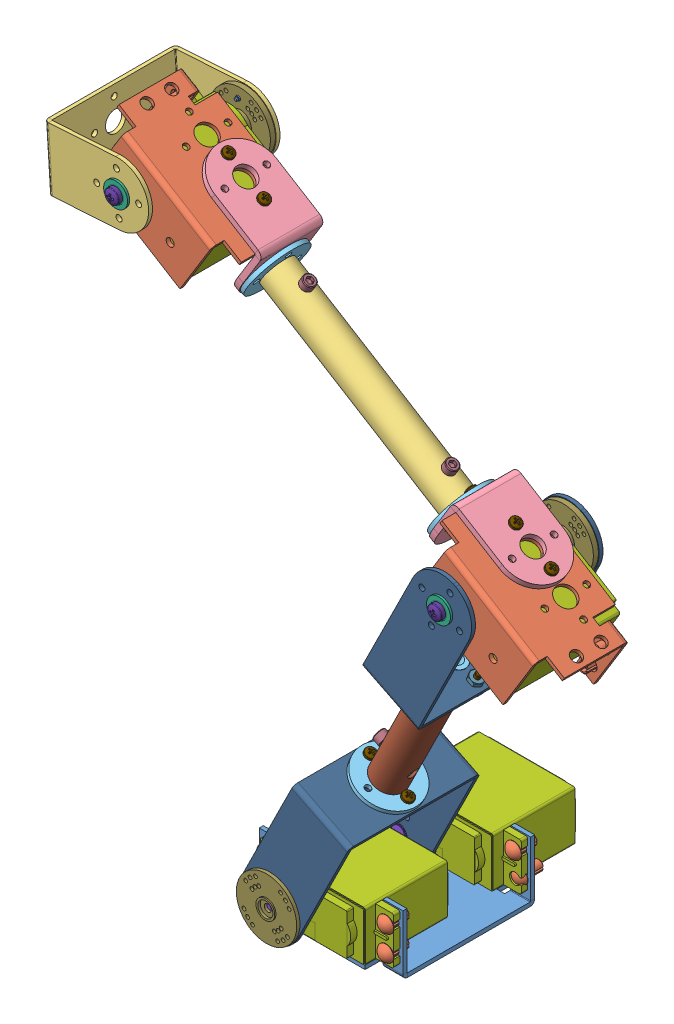
SolidWorks assembly AlumTubeArm-Assy, configuration Default. Lengths in mm.
Overall size (198.02 254.38 96.04).
100 component instances, 21 part files, 161 mates.
Components (placement in the parent):
- asb-13-1: asb-13 [Default] at origin size (57.15 23.83 60.32)
- asb-04-1: asb-04 [Default] at (103.3005 157.352 -10.0457) x (-0.851621 0.524158 0) z (0 0 1) size (57.15 24.21 34.72)
- asb-04-2: asb-04 [Default] at (-25.1454 236.4083 -10.0457) x (-0.851621 0.524158 0) z (0 0 1) size (57.15 24.21 34.72)
- at-06-1: at-06 [Default] at (-4.255 208.2501 -15.4686) x (0 0 1) z (0.851621 -0.524158 0) size (12.7 12.7 85.72)
- asb-06-1: asb-06 [Default] at (78.1303 175.5281 -15.4686) x (-0.851621 0.524158 0) z (0 0 1) size (34.92 27.61 24.59)
- hub-08-1: hub-08 [Default] at (71.4542 161.6524 -15.4686) x (0.524158 0.851621 0) z (0 0 1) size (23.8 16.66 23.8)
- BB-03-1: BB-03 [Default] at (87.3605 150.4009 12.1026) x (0 0 1) z (0.682176 0.731188 0) size (4 9.5 9.5)
- asb-06-2: asb-06 [Default] at (2.4212 222.1258 -15.4686) x (0.851621 -0.524158 0) z (0 0 -1) size (34.92 27.61 24.59)
- hub-08-2: hub-08 [Default] at (-6.9588 209.9143 -15.4686) x (-0.524158 -0.851621 0) z (0 0 1) size (23.8 16.66 23.8)
- Servo_complete-3: Servo_complete [Default] at (29.3908 13.9408 -5.6384) x (-1 0 0) z (0 1 0) size (53 41.78 19.8)
  - Servo_case-1: Servo_case [Default] at origin size (53 38.29 19.8)
  - Output_shaft-1: Output_shaft [Default] at (10 3.0362 0) size (5.71 7.87 5.71)
  - Binding Head Screw_AI-1: Binding Head Screw_AI [CR-BHMS 0.06-80x0.625x0.625-S] at (-17.241 -25.1288 7.741) x (0 1 0) z (0 0 1) size (31.27 3.2 3.2)
  - Binding Head Screw_AI-2: Binding Head Screw_AI [CR-BHMS 0.06-80x0.625x0.625-S] at (-17.241 -25.1288 -7.741) x (0 1 0) z (0 0 1) size (31.27 3.2 3.2)
  - Binding Head Screw_AI-3: Binding Head Screw_AI [CR-BHMS 0.06-80x0.625x0.625-S] at (17.241 -25.1288 7.741) x (0 1 0) z (0 0 1) size (31.27 3.2 3.2)
  - Binding Head Screw_AI-4: Binding Head Screw_AI [CR-BHMS 0.06-80x0.625x0.625-S] at (17.241 -25.1288 -7.741) x (0 1 0) z (0 0 1) size (31.27 3.2 3.2)
- Servo_complete-2: Servo_complete [Default] at (29.3908 13.9408 -56.4511) x (-1 0 0) z (0 1 0) size (53 41.78 19.8)
  - Servo_case-1: Servo_case [Default] at origin size (53 38.29 19.8)
  - Output_shaft-1: Output_shaft [Default] at (10 3.0362 0) size (5.71 7.87 5.71)
  - Binding Head Screw_AI-1: Binding Head Screw_AI [CR-BHMS 0.06-80x0.625x0.625-S] at (-17.241 -25.1288 7.741) x (0 1 0) z (0 0 1) size (31.27 3.2 3.2)
  - Binding Head Screw_AI-2: Binding Head Screw_AI [CR-BHMS 0.06-80x0.625x0.625-S] at (-17.241 -25.1288 -7.741) x (0 1 0) z (0 0 1) size (31.27 3.2 3.2)
  - Binding Head Screw_AI-3: Binding Head Screw_AI [CR-BHMS 0.06-80x0.625x0.625-S] at (17.241 -25.1288 7.741) x (0 1 0) z (0 0 1) size (31.27 3.2 3.2)
  - Binding Head Screw_AI-4: Binding Head Screw_AI [CR-BHMS 0.06-80x0.625x0.625-S] at (17.241 -25.1288 -7.741) x (0 1 0) z (0 0 1) size (31.27 3.2 3.2)
- Servo_complete-1: Servo_complete [Default] at (-32.5692 224.2156 -21.7428) x (-0.851621 0.524158 0) z (-0.524158 -0.851621 0) size (53 41.78 19.8)
  - Servo_case-1: Servo_case [Default] at origin size (53 38.29 19.8)
  - Output_shaft-1: Output_shaft [Default] at (10 3.0362 0) size (5.71 7.87 5.71)
  - Binding Head Screw_AI-1: Binding Head Screw_AI [CR-BHMS 0.06-80x0.625x0.625-S] at (-17.241 -25.1288 7.741) x (0 1 0) z (0 0 1) size (31.27 3.2 3.2)
  - Binding Head Screw_AI-2: Binding Head Screw_AI [CR-BHMS 0.06-80x0.625x0.625-S] at (-17.241 -25.1288 -7.741) x (0 1 0) z (0 0 1) size (31.27 3.2 3.2)
  - Binding Head Screw_AI-3: Binding Head Screw_AI [CR-BHMS 0.06-80x0.625x0.625-S] at (17.241 -25.1288 7.741) x (0 1 0) z (0 0 1) size (31.27 3.2 3.2)
  - Binding Head Screw_AI-4: Binding Head Screw_AI [CR-BHMS 0.06-80x0.625x0.625-S] at (17.241 -25.1288 -7.741) x (0 1 0) z (0 0 1) size (31.27 3.2 3.2)
- BB-03-2: BB-03 [Default] at (-41.0855 229.4572 12.1026) x (0 0 1) z (-0.999072 -0.043064 0) size (4 9.5 9.5)
- Servo_complete-4: Servo_complete [Default] at (95.8767 145.1594 -21.7428) x (-0.851621 0.524158 0) z (-0.524158 -0.851621 0) size (53 41.78 19.8)
  - Servo_case-1: Servo_case [Default] at origin size (53 38.29 19.8)
  - Output_shaft-1: Output_shaft [Default] at (10 3.0362 0) size (5.71 7.87 5.71)
  - Binding Head Screw_AI-1: Binding Head Screw_AI [CR-BHMS 0.06-80x0.625x0.625-S] at (-17.241 -25.1288 7.741) x (0 1 0) z (0 0 1) size (31.27 3.2 3.2)
  - Binding Head Screw_AI-2: Binding Head Screw_AI [CR-BHMS 0.06-80x0.625x0.625-S] at (-17.241 -25.1288 -7.741) x (0 1 0) z (0 0 1) size (31.27 3.2 3.2)
  - Binding Head Screw_AI-3: Binding Head Screw_AI [CR-BHMS 0.06-80x0.625x0.625-S] at (17.241 -25.1288 7.741) x (0 1 0) z (0 0 1) size (31.27 3.2 3.2)
  - Binding Head Screw_AI-4: Binding Head Screw_AI [CR-BHMS 0.06-80x0.625x0.625-S] at (17.241 -25.1288 -7.741) x (0 1 0) z (0 0 1) size (31.27 3.2 3.2)
- asb-10-1: asb-10 [Default] at (39.9278 55.1721 -14.8713) x (0 0 -1) z (-0.895109 0.445847 0) size (52.25 58.34 24.61)
- hub-08-3: hub-08 [Default] at (39.22 53.7511 -14.8713) x (-0.895109 0.445847 0) z (0 0 -1) size (23.8 16.66 23.8)
- asb-10-2: asb-10 [Default] at (66.8235 109.1696 -14.8713) x (0 0 -1) z (0.895109 -0.445847 0) size (52.25 58.34 24.61)
- hub-08-4: hub-08 [Default] at (67.5313 110.5906 -14.8713) x (-0.895109 0.445847 0) z (0 0 1) size (23.8 16.66 23.8)
- at-05-1: at-05 [Default] at (66.1157 107.7486 -14.8713) x (0 0 -1) z (-0.445847 -0.895109 0) size (12.7 12.7 57.15)
- ServoHornPlastic-1: ServoHornPlastic [Default] at (87.3605 150.4009 -39.4712) x (0.649855 0.760058 0) z (-0.760058 0.649855 0) size (24 5 24)
- ServoHornPlastic-2: ServoHornPlastic [Default] at (-41.0855 229.4572 -39.4712) x (0.649855 0.760058 0) z (-0.760058 0.649855 0) size (24 5 24)
- 4-40 x 0.250 SHCS (SHS-01)-1: 4-40 x 0.250 SHCS (SHS-01) [Default] at (8.6763 211.088 -15.4686) x (-0.524158 -0.851621 0) z (0.750627 -0.461998 0.472352) size (9.19 4.65 4.65)
- 4-40 x 0.250 SHCS (SHS-01)-2: 4-40 x 0.250 SHCS (SHS-01) [Default] at (65.4581 176.1397 -15.4686) x (-0.524158 -0.851621 0) z (0.750627 -0.461998 0.472352) size (9.19 4.65 4.65)
- Nut Hex 2-56 (SN-02)-1: Nut Hex 2-56 (SN-02) [Default] at (-4.6145 218.2541 -15.4686) x (0 0 -1) z (-0.851621 0.524158 0) size (4.78 5.51 1.68)
- Nut Hex 2-56 (SN-02)-2: Nut Hex 2-56 (SN-02) [Default] at (-13.3482 204.0641 -15.4686) x (0 0 -1) z (-0.851621 0.524158 0) size (4.78 5.51 1.68)
- Washer Lock M3-1: Washer Lock M3 [Default] at (87.3605 150.4009 7.3152) x (0 0 -1) z (-0.98149 0.191515 0) size (0.79 5.99 5.99)
- Nut Hex M3-1: Nut Hex M3 [Default] at (87.3605 150.4009 2.8912) x (-0.979989 -0.199051 0) z (0 0 -1) size (5.5 6.35 2.9)
- Nut Hex 2-56 (SN-02)-3: Nut Hex 2-56 (SN-02) [Default] at (69.1098 153.3126 -15.4686) x (0 0 1) z (0.851621 -0.524158 0) size (4.78 5.51 1.68)
- Nut Hex 2-56 (SN-02)-4: Nut Hex 2-56 (SN-02) [Default] at (77.8435 167.5026 -15.4686) x (0 0 1) z (0.851621 -0.524158 0) size (4.78 5.51 1.68)
- M3 X 8 LG PHMS (PHS-00)-1: M3 X 8 LG PHMS (PHS-00) [Default] at (87.3605 150.4009 14.5026) x (0 0 -1) z (-0.98149 0.191515 0) size (10.37 5.6 5.6)
- Washer Lock M3-2: Washer Lock M3 [Default] at (-41.0855 229.4572 8.1026) x (0 0 1) z (-0.996303 -0.085907 0) size (0.79 5.99 5.99)
- M3 X 8 LG PHMS (PHS-00)-2: M3 X 8 LG PHMS (PHS-00) [Default] at (-41.0855 229.4572 14.5026) x (0 0 -1) z (0.999989 0.004703 0) size (10.37 5.6 5.6)
- Nut Hex 2-56 (SN-02)-5: Nut Hex 2-56 (SN-02) [Default] at (-41.0855 229.4572 4.1148) x (0.923728 0.383049 0) z (0 0 -1) size (4.78 5.51 1.68)
- 2-56 X 0.250 PHS (PHS-02)-5: 2-56 X 0.250 PHS (PHS-02) [Default] at (71.776 171.2371 -15.4686) x (0.851621 -0.524158 0) z (0 0 1) size (7.89 4.24 4.24)
- 2-56 X 0.250 PHS (PHS-02)-6: 2-56 X 0.250 PHS (PHS-02) [Default] at (63.0423 157.0471 -15.4686) x (0.851621 -0.524158 0) z (0 0 1) size (7.89 4.24 4.24)
- #2 X 0.250 PHTS (PHTS-01)-1: #2 X 0.250 PHTS (PHTS-01) [Default] at (94.8178 146.6865 -40.9952) x (0 0 1) z (-1 0 0) size (6.96 5.97 5.51)
- #2 X 0.250 PHTS (PHTS-01)-2: #2 X 0.250 PHTS (PHTS-01) [Default] at (79.9031 154.1154 -40.9952) x (0 0 1) z (-1 0 0) size (6.96 5.97 5.51)
- Nut Hex 2-56 (SN-02)-10: Nut Hex 2-56 (SN-02) [Default] at (45.9582 48.593 -14.8713) x (0 0 -1) z (-0.445847 -0.895109 0) size (4.78 5.51 1.68)
- Nut Hex 2-56 (SN-02)-11: Nut Hex 2-56 (SN-02) [Default] at (31.0436 56.0219 -14.8713) x (0 0 -1) z (-0.445847 -0.895109 0) size (4.78 5.51 1.68)
- Nut Hex 2-56 (SN-02)-12: Nut Hex 2-56 (SN-02) [Default] at (75.7077 108.3199 -14.8713) x (0 0 -1) z (0.445847 0.895109 0) size (4.78 5.51 1.68)
- Nut Hex 2-56 (SN-02)-13: Nut Hex 2-56 (SN-02) [Default] at (60.793 115.7488 -14.8713) x (0 0 -1) z (0.445847 0.895109 0) size (4.78 5.51 1.68)
- 4-40 x 0.250 SHCS (SHS-01)-3: 4-40 x 0.250 SHCS (SHS-01) [Default] at (36.6519 69.2185 -14.8713) x (0.895109 -0.445847 0) z (-0.344213 -0.691063 -0.635571) size (9.19 4.65 4.65)
- 4-40 x 0.250 SHCS (SHS-01)-4: 4-40 x 0.250 SHCS (SHS-01) [Default] at (53.6387 103.3222 -14.8713) x (0.895109 -0.445847 0) z (-0.351192 -0.705075 -0.616063) size (9.19 4.65 4.65)
- 2-56 X 0.250 PHS (PHS-02)-11: 2-56 X 0.250 PHS (PHS-02) [Default] at (57.9562 110.0534 -14.8713) x (0.445847 0.895109 0) z (-0.895109 0.445847 0) size (7.89 4.24 4.24)
- 2-56 X 0.250 PHS (PHS-02)-12: 2-56 X 0.250 PHS (PHS-02) [Default] at (72.8709 102.6246 -14.8713) x (0.445847 0.895109 0) z (-0.895109 0.445847 0) size (7.89 4.24 4.24)
- 2-56 X 0.250 PHS (PHS-02)-13: 2-56 X 0.250 PHS (PHS-02) [Default] at (33.8804 61.7172 -14.8713) x (-0.445847 -0.895109 0) z (-0.895109 0.445847 0) size (7.89 4.24 4.24)
- 2-56 X 0.250 PHS (PHS-02)-14: 2-56 X 0.250 PHS (PHS-02) [Default] at (48.795 54.2883 -14.8713) x (-0.445847 -0.895109 0) z (-0.895109 0.445847 0) size (7.89 4.24 4.24)
- #2 X 0.250 PHTS (PHTS-01)-3: #2 X 0.250 PHTS (PHTS-01) [Default] at (-40.5533 221.1303 -40.9952) x (0 0 1) z (-1 0 0) size (6.96 5.97 5.51)
- #2 X 0.250 PHTS (PHTS-01)-4: #2 X 0.250 PHTS (PHTS-01) [Default] at (-41.6176 237.7841 -40.9952) x (0 0 1) z (-1 0 0) size (6.96 5.97 5.51)
- 2-56 X 0.250 PHS (PHS-02)-7: 2-56 X 0.250 PHS (PHS-02) [Default] at (-8.9317 230.9625 -15.4686) x (-0.524158 -0.851621 0) z (0 0 1) size (7.89 4.24 4.24)
- 2-56 X 0.250 PHS (PHS-02)-8: 2-56 X 0.250 PHS (PHS-02) [Default] at (-23.1218 239.6962 -15.4686) x (-0.524158 -0.851621 0) z (0 0 1) size (7.89 4.24 4.24)
- 2-56 X 0.250 PHS (PHS-02)-9: 2-56 X 0.250 PHS (PHS-02) [Default] at (91.1341 169.3737 -15.4686) x (-0.524158 -0.851621 0) z (0 0 1) size (7.89 4.24 4.24)
- 2-56 X 0.250 PHS (PHS-02)-10: 2-56 X 0.250 PHS (PHS-02) [Default] at (105.3242 160.64 -15.4686) x (-0.524158 -0.851621 0) z (0 0 1) size (7.89 4.24 4.24)
- Nut Hex 2-56 (SN-02)-6: Nut Hex 2-56 (SN-02) [Default] at (-12.6329 224.949 -15.4686) x (0.572108 -0.352123 0.740744) z (-0.524158 -0.851621 0) size (4.78 5.51 1.68)
- Nut Hex 2-56 (SN-02)-7: Nut Hex 2-56 (SN-02) [Default] at (-26.8229 233.6827 -15.4686) x (0.572108 -0.352123 0.740744) z (-0.524158 -0.851621 0) size (4.78 5.51 1.68)
- Nut Hex 2-56 (SN-02)-8: Nut Hex 2-56 (SN-02) [Default] at (101.623 154.6265 -15.4686) x (0.572108 -0.352123 0.740744) z (-0.524158 -0.851621 0) size (4.78 5.51 1.68)
- Nut Hex 2-56 (SN-02)-9: Nut Hex 2-56 (SN-02) [Default] at (87.4329 163.3602 -15.4686) x (0.572108 -0.352123 0.740744) z (-0.524158 -0.851621 0) size (4.78 5.51 1.68)
- NSRF-01-1: NSRF-01 [Default] at (118.9364 136.8377 -28.5121) x (0 0 1) z (-1 0 0) size (9.65 6.35 6.35)
- NSRF-01-2: NSRF-01 [Default] at (113.6948 128.3215 -28.5121) x (0 0 1) z (-1 0 0) size (9.65 6.35 6.35)
- NSRF-01-3: NSRF-01 [Default] at (78.0586 161.9973 -28.5121) x (0 0 1) z (-1 0 0) size (9.65 6.35 6.35)
- NSRF-01-4: NSRF-01 [Default] at (72.817 153.481 -28.5121) x (0 0 1) z (-1 0 0) size (9.65 6.35 6.35)
- NSRF-01-5: NSRF-01 [Default] at (-9.5096 215.8939 -28.5121) x (0 0 1) z (-1 0 0) size (9.65 6.35 6.35)
- NSRF-01-6: NSRF-01 [Default] at (-14.7511 207.3777 -28.5121) x (0 0 1) z (-1 0 0) size (9.65 6.35 6.35)
- NSRF-01-7: NSRF-01 [Default] at (-50.3874 241.0535 -28.5121) x (0 0 1) z (-1 0 0) size (9.65 6.35 6.35)
- NSRF-01-8: NSRF-01 [Default] at (-55.6289 232.5373 -28.5121) x (0 0 1) z (-1 0 0) size (9.65 6.35 6.35)
- NSRF-01-9: NSRF-01 [Default] at (5.3908 18.9408 -49.6818) x (0 0 -1) z (1 0 0) size (9.65 6.35 6.35)
- NSRF-01-10: NSRF-01 [Default] at (5.3908 8.9408 -49.6818) x (0 0 -1) z (1 0 0) size (9.65 6.35 6.35)
- NSRF-01-11: NSRF-01 [Default] at (5.3908 18.9408 1.1309) x (0 0 -1) z (1 0 0) size (9.65 6.35 6.35)
- NSRF-01-12: NSRF-01 [Default] at (5.3908 8.9408 1.1309) x (0 0 -1) z (1 0 0) size (9.65 6.35 6.35)
- NSRF-01-13: NSRF-01 [Default] at (53.3908 18.9408 1.1309) x (0 0 -1) z (1 0 0) size (9.65 6.35 6.35)
- NSRF-01-14: NSRF-01 [Default] at (53.3908 8.9408 1.1309) x (0 0 -1) z (1 0 0) size (9.65 6.35 6.35)
- NSRF-01-15: NSRF-01 [Default] at (53.3908 18.9408 -49.6818) x (0 0 -1) z (1 0 0) size (9.65 6.35 6.35)
- NSRF-01-16: NSRF-01 [Default] at (53.3908 8.9408 -52.1818) x (0 0 -1) z (1 0 0) size (9.65 6.35 6.35)
- asb-09-1: asb-09 [Default] at (-69.6023 227.6349 -14.8713) x (0 0 1) z (-0.063773 0.997964 0) size (52.25 40.87 24.61)
- ServoHornPlastic-3: ServoHornPlastic [Default] at (19.3908 13.9408 12.5376) x (-0.658562 0.752526 0) z (0.752526 0.658562 0) size (24 5 24)
- ServoHornPlastic-4: ServoHornPlastic [Default] at (19.3908 13.9408 -40.9952) x (-0.658562 0.752526 0) z (0.752526 0.658562 0) size (24 5 24)
Mates (geometry in assembly coordinates):
- Concentric1: concentric anti-aligned: cylinder of at-06-1; cylinder of 4-40 x 0.250 SHCS (SHS-01)-1
- Tangent1: tangent anti-aligned: cylinder of at-06-1; plane of 4-40 x 0.250 SHCS (SHS-01)-1
- Concentric2: concentric anti-aligned: cylinder of at-06-1; cylinder of 4-40 x 0.250 SHCS (SHS-01)-2
- Tangent2: tangent anti-aligned: cylinder of at-06-1; plane of 4-40 x 0.250 SHCS (SHS-01)-2
- Coincident1: coincident anti-aligned: plane of asb-06-1 through (96.2055 161.7189 -15.4686) normal (-0.524158 -0.851621 0); plane of asb-04-1 through (147.7167 130.0147 -10.0457) normal (0.524158 0.851621 0)
- Concentric3: concentric aligned: cylinder of asb-06-1; cylinder of asb-04-1
- Concentric4: concentric aligned: cylinder of asb-06-1; cylinder of asb-04-1
- Concentric6: concentric aligned: cylinder of asb-04-1; cylinder of Washer Lock M3-1
- Coincident2: coincident anti-aligned: plane of asb-04-1 through (146.9178 128.7168 7.3152) normal (0 0 1); plane of Washer Lock M3-1
- Concentric7: concentric anti-aligned: cylinder of asb-04-1; cylinder of Nut Hex M3-1
- Coincident3: coincident anti-aligned: plane of asb-04-1 through (122.3345 188.2774 5.7912) normal (0 0 -1); plane of Nut Hex M3-1
- Coincident5: coincident anti-aligned: plane of asb-06-2 through (-18.0504 232.0414 -15.4686) normal (-0.524158 -0.851621 0); plane of asb-04-2 through (19.2707 209.0709 -10.0457) normal (0.524158 0.851621 0)
- Concentric8: concentric aligned: cylinder of asb-06-2; cylinder of asb-04-2
- Concentric9: concentric aligned: cylinder of asb-06-2; cylinder of asb-04-2
- Concentric12: concentric anti-aligned: cylinder of asb-06-2; cylinder of Nut Hex 2-56 (SN-02)-1
- Coincident8: coincident anti-aligned: plane of asb-06-2 through (-7.5537 210.2804 -15.4686) normal (-0.851621 0.524158 0); plane of Nut Hex 2-56 (SN-02)-1
- Concentric13: concentric anti-aligned: cylinder of asb-06-2; cylinder of Nut Hex 2-56 (SN-02)-2
- Coincident9: coincident anti-aligned: plane of asb-06-2 through (-7.5537 210.2804 -15.4686) normal (-0.851621 0.524158 0); plane of Nut Hex 2-56 (SN-02)-2
- Concentric14: concentric anti-aligned: cylinder of hub-08-1; cylinder of at-06-1
- Concentric15: concentric anti-aligned: cylinder of hub-08-1; cylinder of at-06-1
- Concentric16: concentric aligned: cylinder of hub-08-2; cylinder of at-06-1
- Concentric17: concentric anti-aligned: cylinder of asb-06-1; cylinder of hub-08-1
- Coincident10: coincident anti-aligned: plane of asb-06-1 through (76.9321 173.5813 -27.7622) normal (-0.851621 0.524158 0); plane of hub-08-1 through (70.1022 162.4845 -37.2766) normal (0.851621 -0.524158 0)
- Concentric18: concentric anti-aligned: cylinder of asb-06-1; cylinder of hub-08-1
- Concentric19: concentric anti-aligned: cylinder of asb-06-1; cylinder of Nut Hex 2-56 (SN-02)-3
- Coincident11: coincident anti-aligned: plane of asb-06-1 through (72.049 161.2863 -15.4686) normal (0.851621 -0.524158 0); plane of Nut Hex 2-56 (SN-02)-3
- Concentric20: concentric anti-aligned: cylinder of asb-06-1; cylinder of Nut Hex 2-56 (SN-02)-4
- Coincident12: coincident anti-aligned: plane of asb-06-1 through (72.049 161.2863 -15.4686) normal (0.851621 -0.524158 0); plane of Nut Hex 2-56 (SN-02)-4
- Coincident13: coincident aligned: plane of asb-06-1 through (96.2055 161.7189 -15.4686) normal (-0.524158 -0.851621 0); plane of asb-06-2 through (-18.0504 232.0414 -15.4686) normal (-0.524158 -0.851621 0)
- Concentric21: concentric anti-aligned: cylinder of asb-06-1; cylinder of asb-06-2
- Coincident16: coincident anti-aligned: plane of Washer Lock M3-1; plane of BB-03-1 through (89.0641 148.8115 8.1026) normal (0 0 -1)
- Concentric27: concentric anti-aligned: cylinder of asb-06-2; cylinder of hub-08-2
- Coincident19: coincident anti-aligned: plane of asb-06-2 through (1.223 220.179 -3.175) normal (0.851621 -0.524158 0); plane of hub-08-2 through (-5.6069 209.0822 -37.2766) normal (-0.851621 0.524158 0)
- Concentric28: concentric anti-aligned: cylinder of asb-06-2; cylinder of hub-08-2
- Concentric341: concentric anti-aligned: cylinder of BB-03-2; cylinder of Washer Lock M3-2
- Coincident241: coincident anti-aligned: plane of BB-03-2 through (-41.2577 233.4535 8.1026) normal (0 0 -1); plane of Washer Lock M3-2
- Coincident25: coincident anti-aligned: plane of asb-04-2 through (18.4719 207.773 7.3152) normal (0 0 1); plane of Washer Lock M3-2
- Concentric371: concentric anti-aligned: cylinder of asb-04-2; cylinder of Nut Hex 2-56 (SN-02)-5
- Coincident271: coincident anti-aligned: plane of asb-04-2 through (-6.1114 267.3336 5.7912) normal (0 0 -1); plane of Nut Hex 2-56 (SN-02)-5
- Coincident272: coincident anti-aligned: plane of asb-13-1 through (-36.2013 23.8252 -3.9624) normal (0 0 1); plane of Servo_complete-3/Servo_case-1 through (55.8908 23.3408 -3.9624) normal (0 0 -1)
- Parallel1: parallel aligned: plane of asb-13-1 through (57.15 23.8252 -52.3041) normal (1 0 0); plane of Servo_complete-3/Servo_case-1 through (55.8908 4.5408 -3.9624) normal (1 0 0)
- Coincident273: coincident anti-aligned: plane of asb-13-1 through (-36.2013 23.8252 -54.7751) normal (0 0 1); plane of Servo_complete-2/Servo_case-1 through (55.8908 23.3408 -54.7751) normal (0 0 -1)
- Parallel2: parallel aligned: plane of asb-13-1 through (57.15 23.8252 -8.0209) normal (1 0 0); plane of Servo_complete-2/Servo_case-1 through (55.8908 4.5408 -54.7751) normal (1 0 0)
- Concentric376: concentric aligned: cylinder of asb-13-1; cylinder of Servo_complete-3/Servo_case-1
- Concentric377: concentric aligned: cylinder of asb-13-1; cylinder of Servo_complete-2/Servo_case-1
- Coincident275: coincident anti-aligned: plane of asb-04-2 through (18.4719 207.773 -23.4188) normal (0 0 -1); plane of Servo_complete-1/Servo_case-1 through (-60.0643 230.1005 -23.4188) normal (0 0 1)
- Parallel3: parallel aligned: plane of asb-04-2 through (19.2707 209.0709 -10.0457) normal (0.524158 0.851621 0); plane of Servo_complete-1/Servo_case-1 through (-11.5076 222.8774 -29.9978) normal (0.524158 0.851621 0)
- Coincident276: coincident anti-aligned: plane of asb-04-1 through (146.9178 128.7168 -23.4188) normal (0 0 -1); plane of Servo_complete-4/Servo_case-1 through (68.3816 151.0443 -23.4188) normal (0 0 1)
- Parallel4: parallel aligned: plane of asb-04-1 through (147.7167 130.0147 -10.0457) normal (0.524158 0.851621 0); plane of Servo_complete-4/Servo_case-1 through (116.9384 143.8212 -29.9978) normal (0.524158 0.851621 0)
- Concentric380: concentric aligned: cylinder of BB-03-1; cylinder of M3 X 8 LG PHMS (PHS-00)-1
- Coincident277: coincident anti-aligned: plane of BB-03-1 through (88.4572 149.3777 12.1026) normal (0 0 1); plane of M3 X 8 LG PHMS (PHS-00)-1
- Concentric3811: concentric anti-aligned: cylinder of hub-08-1; cylinder of 2-56 X 0.250 PHS (PHS-02)-5
- Coincident2781: coincident anti-aligned: plane of hub-08-1 through (68.7503 163.3166 -37.2766) normal (-0.851621 0.524158 0); plane of 2-56 X 0.250 PHS (PHS-02)-5
- Concentric3821: concentric anti-aligned: cylinder of hub-08-1; cylinder of 2-56 X 0.250 PHS (PHS-02)-6
- Coincident2791: coincident anti-aligned: plane of hub-08-1 through (68.7503 163.3166 -37.2766) normal (-0.851621 0.524158 0); plane of 2-56 X 0.250 PHS (PHS-02)-6
- Concentric383: concentric anti-aligned: cylinder of Servo_complete-4/Servo_case-1; cylinder of ServoHornPlastic-1
- Concentric386: concentric aligned: cylinder of BB-03-2; cylinder of M3 X 8 LG PHMS (PHS-00)-2
- Coincident283: coincident anti-aligned: plane of BB-03-2 through (-41.1501 230.9558 12.1026) normal (0 0 1); plane of M3 X 8 LG PHMS (PHS-00)-2
- Concentric387: concentric anti-aligned: cylinder of Servo_complete-1/Servo_case-1; cylinder of ServoHornPlastic-2
- Concentric3901: concentric aligned: cylinder of asb-06-2; cylinder of 2-56 X 0.250 PHS (PHS-02)-7
- Coincident2871: coincident anti-aligned: plane of asb-06-2 through (-16.8522 233.9882 -15.4686) normal (0.524158 0.851621 0); plane of 2-56 X 0.250 PHS (PHS-02)-7
- Concentric3911: concentric aligned: cylinder of asb-06-2; cylinder of 2-56 X 0.250 PHS (PHS-02)-8
- Coincident2881: coincident anti-aligned: plane of asb-06-2 through (-16.8522 233.9882 -15.4686) normal (0.524158 0.851621 0); plane of 2-56 X 0.250 PHS (PHS-02)-8
- Concentric3921: concentric aligned: cylinder of asb-06-1; cylinder of 2-56 X 0.250 PHS (PHS-02)-9
- Coincident2891: coincident anti-aligned: plane of asb-06-1 through (97.4037 163.6657 -15.4686) normal (0.524158 0.851621 0); plane of 2-56 X 0.250 PHS (PHS-02)-9
- Concentric3931: concentric aligned: cylinder of asb-06-1; cylinder of 2-56 X 0.250 PHS (PHS-02)-10
- Coincident2901: coincident anti-aligned: plane of asb-06-1 through (97.4037 163.6657 -15.4686) normal (0.524158 0.851621 0); plane of 2-56 X 0.250 PHS (PHS-02)-10
- Concentric3941: concentric anti-aligned: cylinder of asb-04-2; cylinder of Nut Hex 2-56 (SN-02)-6
- Coincident2911: coincident anti-aligned: plane of asb-04-2 through (18.4719 207.773 -10.0457) normal (-0.524158 -0.851621 0); plane of Nut Hex 2-56 (SN-02)-6
- Concentric3951: concentric anti-aligned: cylinder of asb-04-2; cylinder of Nut Hex 2-56 (SN-02)-7
- Coincident2921: coincident anti-aligned: plane of asb-04-2 through (18.4719 207.773 -10.0457) normal (-0.524158 -0.851621 0); plane of Nut Hex 2-56 (SN-02)-7
- Concentric3961: concentric anti-aligned: cylinder of asb-04-1; cylinder of Nut Hex 2-56 (SN-02)-8
- Coincident2931: coincident anti-aligned: plane of asb-04-1 through (146.9178 128.7168 -10.0457) normal (-0.524158 -0.851621 0); plane of Nut Hex 2-56 (SN-02)-8
- Concentric3971: concentric anti-aligned: cylinder of asb-04-1; cylinder of Nut Hex 2-56 (SN-02)-9
- Coincident2941: coincident anti-aligned: plane of asb-04-1 through (146.9178 128.7168 -10.0457) normal (-0.524158 -0.851621 0); plane of Nut Hex 2-56 (SN-02)-9
- Concentric3981: concentric aligned: cylinder of Servo_complete-4/Servo_case-1; cylinder of NSRF-01-1
- Coincident2951: coincident anti-aligned: plane of Servo_complete-4/Servo_case-1 through (113.5176 123.2639 -25.9188) normal (0 0 -1); plane of NSRF-01-1 through (118.9364 138.1155 -25.9188) normal (0 0 1)
- Concentric3991: concentric aligned: cylinder of Servo_complete-4/Servo_case-1; cylinder of NSRF-01-2
- Coincident2961: coincident anti-aligned: plane of Servo_complete-4/Servo_case-1 through (113.5176 123.2639 -25.9188) normal (0 0 -1); plane of NSRF-01-2 through (113.6948 129.5993 -25.9188) normal (0 0 1)
- Concentric4001: concentric aligned: cylinder of Servo_complete-4/Servo_case-1; cylinder of NSRF-01-3
- Coincident2971: coincident anti-aligned: plane of Servo_complete-4/Servo_case-1 through (68.3816 151.0443 -25.9188) normal (0 0 -1); plane of NSRF-01-3 through (78.0586 163.2751 -25.9188) normal (0 0 1)
- Concentric4011: concentric aligned: cylinder of Servo_complete-4/Servo_case-1; cylinder of NSRF-01-4
- Coincident2981: coincident anti-aligned: plane of Servo_complete-4/Servo_case-1 through (68.3816 151.0443 -25.9188) normal (0 0 -1); plane of NSRF-01-4 through (72.817 154.7589 -25.9188) normal (0 0 1)
- Concentric4021: concentric aligned: cylinder of Servo_complete-1/Servo_case-1; cylinder of NSRF-01-5
- Coincident2991: coincident anti-aligned: plane of Servo_complete-1/Servo_case-1 through (-14.9284 202.3202 -25.9188) normal (0 0 -1); plane of NSRF-01-5 through (-9.5096 217.1717 -25.9188) normal (0 0 1)
- Concentric4031: concentric aligned: cylinder of Servo_complete-1/Servo_case-1; cylinder of NSRF-01-6
- Coincident3001: coincident anti-aligned: plane of Servo_complete-1/Servo_case-1 through (-14.9284 202.3202 -25.9188) normal (0 0 -1); plane of NSRF-01-6 through (-14.7511 208.6555 -25.9188) normal (0 0 1)
- Concentric4041: concentric aligned: cylinder of Servo_complete-1/Servo_case-1; cylinder of NSRF-01-7
- Coincident3011: coincident anti-aligned: plane of Servo_complete-1/Servo_case-1 through (-60.0643 230.1005 -25.9188) normal (0 0 -1); plane of NSRF-01-7 through (-50.3874 242.3313 -25.9188) normal (0 0 1)
- Concentric4051: concentric aligned: cylinder of Servo_complete-1/Servo_case-1; cylinder of NSRF-01-8
- Coincident3021: coincident anti-aligned: plane of Servo_complete-1/Servo_case-1 through (-60.0643 230.1005 -25.9188) normal (0 0 -1); plane of NSRF-01-8 through (-55.6289 233.8151 -25.9188) normal (0 0 1)
- Concentric4061: concentric aligned: cylinder of Servo_complete-2/Servo_case-1; cylinder of NSRF-01-9
- Coincident3031: coincident anti-aligned: plane of Servo_complete-2/Servo_case-1 through (2.8908 23.3408 -52.2751) normal (0 0 1); plane of NSRF-01-9 through (5.3908 20.2186 -52.2751) normal (0 0 -1)
- Concentric4071: concentric aligned: cylinder of Servo_complete-2/Servo_case-1; cylinder of NSRF-01-10
- Coincident3041: coincident anti-aligned: plane of Servo_complete-2/Servo_case-1 through (2.8908 23.3408 -52.2751) normal (0 0 1); plane of NSRF-01-10 through (5.3908 10.2186 -52.2751) normal (0 0 -1)
- Concentric4081: concentric aligned: cylinder of Servo_complete-3/Servo_case-1; cylinder of NSRF-01-11
- Coincident3051: coincident anti-aligned: plane of Servo_complete-3/Servo_case-1 through (2.8908 23.3408 -1.4624) normal (0 0 1); plane of NSRF-01-11 through (5.3908 20.2186 -1.4624) normal (0 0 -1)
- Concentric4091: concentric aligned: cylinder of Servo_complete-3/Servo_case-1; cylinder of NSRF-01-12
- Coincident3061: coincident anti-aligned: plane of Servo_complete-3/Servo_case-1 through (2.8908 23.3408 -1.4624) normal (0 0 1); plane of NSRF-01-12 through (5.3908 10.2186 -1.4624) normal (0 0 -1)
- Concentric4101: concentric aligned: cylinder of Servo_complete-3/Servo_case-1; cylinder of NSRF-01-13
- Coincident3071: coincident anti-aligned: plane of Servo_complete-3/Servo_case-1 through (55.8908 23.3408 -1.4624) normal (0 0 1); plane of NSRF-01-13 through (53.3908 20.2186 -1.4624) normal (0 0 -1)
- Concentric4111: concentric aligned: cylinder of Servo_complete-3/Servo_case-1; cylinder of NSRF-01-14
- Coincident3081: coincident anti-aligned: plane of Servo_complete-3/Servo_case-1 through (55.8908 23.3408 -1.4624) normal (0 0 1); plane of NSRF-01-14 through (53.3908 10.2186 -1.4624) normal (0 0 -1)
- Concentric4121: concentric aligned: cylinder of Servo_complete-2/Servo_case-1; cylinder of NSRF-01-15
- Coincident3091: coincident anti-aligned: plane of Servo_complete-2/Servo_case-1 through (55.8908 23.3408 -52.2751) normal (0 0 1); plane of NSRF-01-15 through (53.3908 20.2186 -52.2751) normal (0 0 -1)
- Concentric4131: concentric aligned: cylinder of asb-13-1; cylinder of NSRF-01-16
- Coincident3101: coincident anti-aligned: plane of asb-13-1 through (-36.2013 23.8252 -54.7751) normal (0 0 1); plane of NSRF-01-16 through (53.3908 10.2186 -54.7751) normal (0 0 -1)
- Concentric414: concentric anti-aligned: cylinder of asb-10-1; cylinder of hub-08-3
- Coincident311: coincident anti-aligned: plane of asb-10-1 through (39.9278 55.1721 30.1928) normal (0.445847 0.895109 0); plane of hub-08-3 through (39.9278 55.1721 6.9367) normal (-0.445847 -0.895109 0)
- Concentric415: concentric anti-aligned: cylinder of asb-10-1; cylinder of hub-08-3
- Concentric416: concentric anti-aligned: cylinder of asb-10-1; cylinder of Nut Hex 2-56 (SN-02)-10
- Coincident312: coincident anti-aligned: plane of asb-10-1 through (39.2483 53.808 30.1928) normal (-0.445847 -0.895109 0); plane of Nut Hex 2-56 (SN-02)-10
- Concentric417: concentric anti-aligned: cylinder of asb-10-1; cylinder of Nut Hex 2-56 (SN-02)-11
- Coincident313: coincident anti-aligned: plane of asb-10-1 through (39.2483 53.808 30.1928) normal (-0.445847 -0.895109 0); plane of Nut Hex 2-56 (SN-02)-11
- Concentric418: concentric anti-aligned: cylinder of asb-10-1; cylinder of asb-10-2
- Coincident314: coincident aligned: plane of asb-10-1 through (13.9154 2.9481 9.7286) normal (0 0 -1); plane of asb-10-2 through (92.8359 161.3937 9.7286) normal (0 0 -1)
- Concentric419: concentric anti-aligned: cylinder of hub-08-3; cylinder of at-05-1
- Concentric420: concentric anti-aligned: cylinder of hub-08-3; cylinder of 2-56 X 0.250 PHS (PHS-02)-13
- Coincident315: coincident anti-aligned: plane of hub-08-3 through (40.6356 56.5931 6.9367) normal (0.445847 0.895109 0); plane of 2-56 X 0.250 PHS (PHS-02)-13
- Concentric421: concentric anti-aligned: cylinder of hub-08-3; cylinder of 2-56 X 0.250 PHS (PHS-02)-14
- Coincident316: coincident anti-aligned: plane of hub-08-3 through (40.6356 56.5931 6.9367) normal (0.445847 0.895109 0); plane of 2-56 X 0.250 PHS (PHS-02)-14
- Concentric422: concentric anti-aligned: cylinder of asb-10-2; cylinder of hub-08-4
- Coincident317: coincident anti-aligned: plane of asb-10-2 through (66.8235 109.1696 30.1928) normal (-0.445847 -0.895109 0); plane of hub-08-4 through (66.8235 109.1696 -36.6793) normal (0.445847 0.895109 0)
- Concentric423: concentric anti-aligned: cylinder of asb-10-2; cylinder of hub-08-4
- Concentric424: concentric anti-aligned: cylinder of asb-10-2; cylinder of Nut Hex 2-56 (SN-02)-12
- Coincident318: coincident anti-aligned: plane of asb-10-2 through (67.5029 110.5338 30.1928) normal (0.445847 0.895109 0); plane of Nut Hex 2-56 (SN-02)-12
- Concentric425: concentric anti-aligned: cylinder of asb-10-2; cylinder of Nut Hex 2-56 (SN-02)-13
- Coincident319: coincident anti-aligned: plane of asb-10-2 through (67.5029 110.5338 30.1928) normal (0.445847 0.895109 0); plane of Nut Hex 2-56 (SN-02)-13
- Concentric426: concentric aligned: cylinder of hub-08-4; cylinder of at-05-1
- Concentric427: concentric anti-aligned: cylinder of hub-08-4; cylinder of at-05-1
- Concentric428: concentric anti-aligned: cylinder of hub-08-4; cylinder of 2-56 X 0.250 PHS (PHS-02)-11
- Coincident320: coincident anti-aligned: plane of hub-08-4 through (66.1157 107.7486 -36.6793) normal (-0.445847 -0.895109 0); plane of 2-56 X 0.250 PHS (PHS-02)-11
- Concentric429: concentric anti-aligned: cylinder of hub-08-4; cylinder of 2-56 X 0.250 PHS (PHS-02)-12
- Coincident321: coincident anti-aligned: plane of hub-08-4 through (66.1157 107.7486 -36.6793) normal (-0.445847 -0.895109 0); plane of 2-56 X 0.250 PHS (PHS-02)-12
- Concentric430: concentric anti-aligned: cylinder of at-05-1; cylinder of 4-40 x 0.250 SHCS (SHS-01)-3
- Tangent3: tangent anti-aligned: cylinder of at-05-1; plane of 4-40 x 0.250 SHCS (SHS-01)-3
- Concentric431: concentric anti-aligned: cylinder of at-05-1; cylinder of 4-40 x 0.250 SHCS (SHS-01)-4
- Tangent4: tangent anti-aligned: cylinder of at-05-1; plane of 4-40 x 0.250 SHCS (SHS-01)-4
- Concentric432: concentric aligned: cylinder of asb-10-1; cylinder of Servo_complete-3/Servo_case-1
- Concentric433: concentric anti-aligned: cylinder of asb-04-1; cylinder of asb-10-2
- Concentric434: concentric anti-aligned: cylinder of asb-10-2; cylinder of BB-03-1
- Coincident322: coincident anti-aligned: plane of asb-10-2 through (92.8359 161.3937 11.2526) normal (0 0 1); plane of BB-03-1 through (90.8336 147.1606 11.2526) normal (0 0 -1)
- Concentric435: concentric anti-aligned: cylinder of asb-10-2; cylinder of Servo_complete-4/Servo_case-1
- Coincident323: coincident anti-aligned: plane of asb-10-2 through (92.8359 161.3937 -39.4712) normal (0 0 1); plane of ServoHornPlastic-1 through (79.5622 141.2802 -39.4712) normal (0 0 -1)
- Concentric436: concentric anti-aligned: cylinder of asb-10-2; cylinder of #2 X 0.250 PHTS (PHTS-01)-1
- Coincident324: coincident anti-aligned: plane of asb-10-2 through (92.8359 161.3937 -40.9952) normal (0 0 -1); plane of #2 X 0.250 PHTS (PHTS-01)-1 through (94.8178 148.2931 -40.9952) normal (0 0 1)
- Concentric437: concentric anti-aligned: cylinder of asb-10-2; cylinder of #2 X 0.250 PHTS (PHTS-01)-2
- Coincident325: coincident anti-aligned: plane of asb-10-2 through (92.8359 161.3937 -40.9952) normal (0 0 -1); plane of #2 X 0.250 PHTS (PHTS-01)-2 through (79.9031 155.7219 -40.9952) normal (0 0 1)
- Concentric440: concentric aligned: cylinder of asb-09-1; cylinder of BB-03-2
- Coincident327: coincident anti-aligned: plane of asb-09-1 through (-25.943 185.2688 11.2526) normal (0 0 1); plane of BB-03-2 through (-41.29 234.2028 11.2526) normal (0 0 -1)
- Concentric441: concentric aligned: cylinder of asb-04-2; cylinder of asb-09-1
- Concentric442: concentric aligned: cylinder of Servo_complete-1/Servo_case-1; cylinder of asb-09-1
- Coincident328: coincident anti-aligned: plane of asb-09-1 through (-25.943 185.2688 -39.4712) normal (0 0 1); plane of ServoHornPlastic-2 through (-48.8837 220.3365 -39.4712) normal (0 0 -1)
- Concentric443: concentric aligned: cylinder of asb-09-1; cylinder of #2 X 0.250 PHTS (PHTS-01)-3
- Coincident329: coincident anti-aligned: plane of asb-09-1 through (-25.943 185.2688 -40.9952) normal (0 0 -1); plane of #2 X 0.250 PHTS (PHTS-01)-3 through (-40.5533 222.7368 -40.9952) normal (0 0 1)
- Concentric444: concentric aligned: cylinder of asb-09-1; cylinder of #2 X 0.250 PHTS (PHTS-01)-4
- Coincident330: coincident anti-aligned: plane of asb-09-1 through (-25.943 185.2688 -40.9952) normal (0 0 -1); plane of #2 X 0.250 PHTS (PHTS-01)-4 through (-41.6176 239.3906 -40.9952) normal (0 0 1)
- Concentric445: concentric anti-aligned: cylinder of Servo_complete-3/Servo_case-1; cylinder of ServoHornPlastic-3
- Coincident331: coincident anti-aligned: plane of Servo_complete-3/Output_shaft-1 through (16.5333 13.9408 11.0376) normal (0 0 1); plane of ServoHornPlastic-3 through (19.3908 13.9408 11.0376) normal (0 0 -1)
- Concentric446: concentric aligned: cylinder of Servo_complete-2/Servo_case-1; cylinder of ServoHornPlastic-4
- Coincident332: coincident anti-aligned: plane of asb-10-1 through (13.9154 2.9481 -40.9952) normal (0 0 -1); plane of ServoHornPlastic-4 through (27.2935 4.9105 -40.9952) normal (0 0 1)
